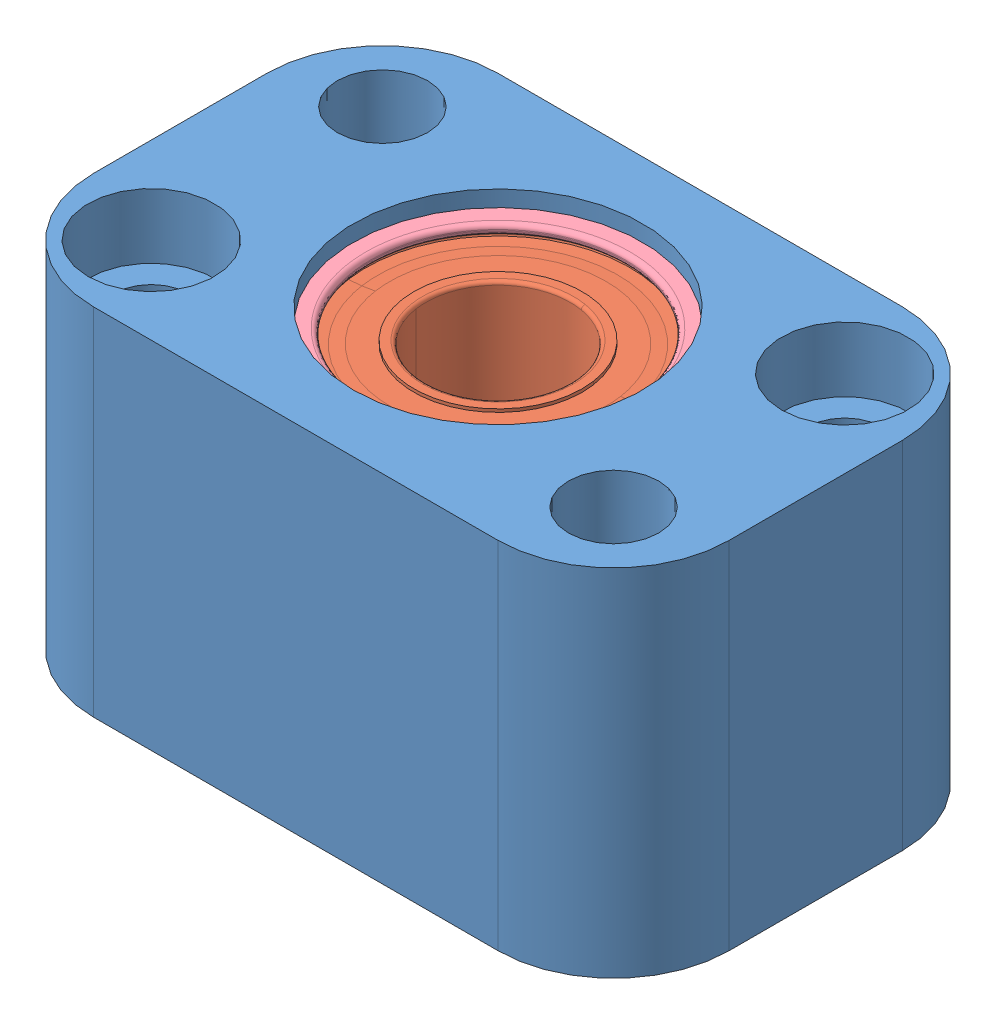
SolidWorks assembly Stabilizer Actuated Assembly, configuration Default. Lengths in mm.
Overall size (27.94 15.62 17.78).
11 component instances, 4 part files, 9 mates.
Components (placement in the parent):
- EXK-02-0012-1: EXK-02-0012 [Default] at origin size (27.94 15.62 17.78)
- D_W_R188_2RS1-1: D_W_R188_2RS1 [Default] at (0 6.5405 0) x (0 -1 0) z (-0.989361 0 0.145483) size (4.76 12.7 12.7)
- D_W_R188_2RS1-2: D_W_R188_2RS1 [Default] at (0 -6.5405 0) x (0 1 0) z (0.953779 0 0.300509) size (4.76 12.7 12.7)
- 91182A604_TYPE 316 STAINLESS STEEL SHIM FOR BEARINGS-1: 91182A604_TYPE 316 STAINLESS STEEL SHIM FOR BEARINGS [91182A604] at (0 -1.2705 0) x (1 0 0) z (0 0 -1) size (12.65 0.51 12.65)
- 91182A604_TYPE 316 STAINLESS STEEL SHIM FOR BEARINGS-2: 91182A604_TYPE 316 STAINLESS STEEL SHIM FOR BEARINGS [91182A604] at (0 -0.7625 0) x (1 0 0) z (0 0 -1) size (12.65 0.51 12.65)
- 91182A604_TYPE 316 STAINLESS STEEL SHIM FOR BEARINGS-3: 91182A604_TYPE 316 STAINLESS STEEL SHIM FOR BEARINGS [91182A604] at (0 -0.2545 0) x (1 0 0) z (0 0 -1) size (12.65 0.51 12.65)
- 91182A604_TYPE 316 STAINLESS STEEL SHIM FOR BEARINGS-4: 91182A604_TYPE 316 STAINLESS STEEL SHIM FOR BEARINGS [91182A604] at (0 0.2535 0) x (1 0 0) z (0 0 -1) size (12.65 0.51 12.65)
- 91182A604_TYPE 316 STAINLESS STEEL SHIM FOR BEARINGS-5: 91182A604_TYPE 316 STAINLESS STEEL SHIM FOR BEARINGS [91182A604] at (0 0.7615 0) x (1 0 0) z (0 0 -1) size (12.65 0.51 12.65)
- 92479A730_EASY INSTALL SPIRAL INTERNAL RETAINING RING-1: 92479A730_EASY INSTALL SPIRAL INTERNAL RETAINING RING [92479A730] at (0 6.7691 0) x (1 0 0) z (0 1 0) size (13.26 13.49 0.52)
- 91182A604_TYPE 316 STAINLESS STEEL SHIM FOR BEARINGS-6: 91182A604_TYPE 316 STAINLESS STEEL SHIM FOR BEARINGS [91182A604] at (0 1.2695 0) x (1 0 0) z (0 0 -1) size (12.65 0.51 12.65)
- 91182A604_TYPE 316 STAINLESS STEEL SHIM FOR BEARINGS-7: 91182A604_TYPE 316 STAINLESS STEEL SHIM FOR BEARINGS [91182A604] at (0 1.7775 0) x (1 0 0) z (0 0 -1) size (12.65 0.51 12.65)
Mates (geometry in assembly coordinates):
- Distance1: distance = 1.27 mm aligned: plane of EXK-02-0012-1 through (-13.97 7.8105 8.89) normal (0 1 0); plane of D_W_R188_2RS1-1 through (0.902 6.5405 6.134) normal (0 1 0)
- Concentric20: concentric anti-aligned: cylinder of EXK-02-0012-1 through (0 -25.771 0) axis (0 1 0) radius 6.35; cylinder of D_W_R188_2RS1-1 through (0 -43.4595 0) axis (0 -1 0) radius 6.35
- Coincident174: coincident anti-aligned: plane of EXK-02-0012-1 through (-13.97 -6.5405 8.89) normal (0 1 0); plane of D_W_R188_2RS1-2 through (-1.8632 -6.5405 5.9134) normal (0 -1 0)
- Concentric21: concentric aligned: cylinder of EXK-02-0012-1 through (0 -7.8105 0) axis (0 1 0) radius 4.7625; cylinder of D_W_R188_2RS1-2 through (0 43.4595 0) axis (0 1 0) radius 6.35
- Coincident175: coincident anti-aligned: plane of D_W_R188_2RS1-2 through (-1.7429 -1.7785 5.5319) normal (0 1 0); plane of 91182A604_TYPE 316 STAINLESS STEEL SHIM FOR BEARINGS-1 through (0 -1.7785 0) normal (0 -1 0)
- Concentric22: concentric aligned: cylinder of D_W_R188_2RS1-2 through (0 43.4595 0) axis (0 1 0) radius 6.35; cylinder of 91182A604_TYPE 316 STAINLESS STEEL SHIM FOR BEARINGS-1 through (0 -1.7785 0) axis (0 1 0) radius 6.3246
- Coincident176: coincident anti-aligned: plane of EXK-02-0012-1 through (0 6.5405 0) normal (0 1 0); plane of 92479A730_EASY INSTALL SPIRAL INTERNAL RETAINING RING-1 through (0 6.5405 0) normal (0 -1 0)
- Concentric23: concentric anti-aligned: circle of EXK-02-0012-1; circle of 92479A730_EASY INSTALL SPIRAL INTERNAL RETAINING RING-1
- Coincident177: coordinate: point of EXK-02-0012-1
